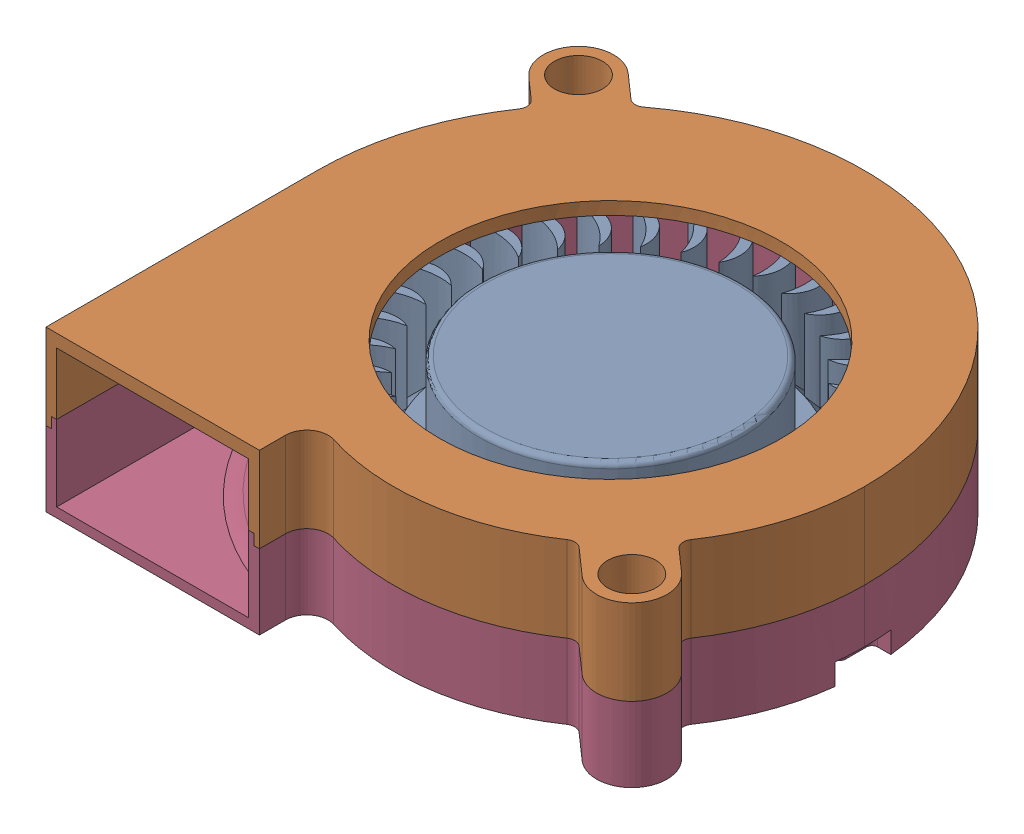
SolidWorks assembly Chimera_Radial-Cooling-Fan-5015-DC12V, configuration По умолчанию. Lengths in mm.
Overall size (51.3 15 51.07).
3 component instances, 3 part files, 5 mates.
Components (placement in the parent):
- Chimera_turbine-1: Chimera_turbine [По умолчанию] at (0 3.2 0) x (0.990476 0 -0.137682) z (0.137682 0 0.990476) size (38.96 10.5 38.91)
- Chimera_top-3: Chimera_top [По умолчанию] at (0 15 0) size (51.3 8 51.07)
- Chimera_bottom-1: Chimera_bottom [По умолчанию] at origin size (51.3 8.5 51.07)
Mates (geometry in assembly coordinates):
- Совпадение5: coordinate: point of Chimera_bottom-1
- Совпадение6: coincident anti-aligned: line of Chimera_top-3 through (-27.5 7 25.4) axis (0 1 0); line of Chimera_bottom-1 through (-27.5 7 25.4) axis (0 -1 0)
- Совпадение7: coincident anti-aligned: plane of Chimera_top-3 through (-23 7 -20) normal (0 -1 0); plane of Chimera_bottom-1 through (-1.85 7 -0.1334) normal (0 1 0)
- Концентричный2: concentric aligned: cylinder of Chimera_turbine-1 through (0 12.9 0) axis (0 -1 0) radius 11.4; cylinder of Chimera_bottom-1 through (0 8 0) axis (0 -1 0) radius 2.5
- Расстояние1: distance = 2 mm anti-aligned: plane of Chimera_turbine-1 through (0 3.2 0) normal (0 -1 0); plane of Chimera_bottom-1 through (-23 1.2 -20) normal (0 1 0)
